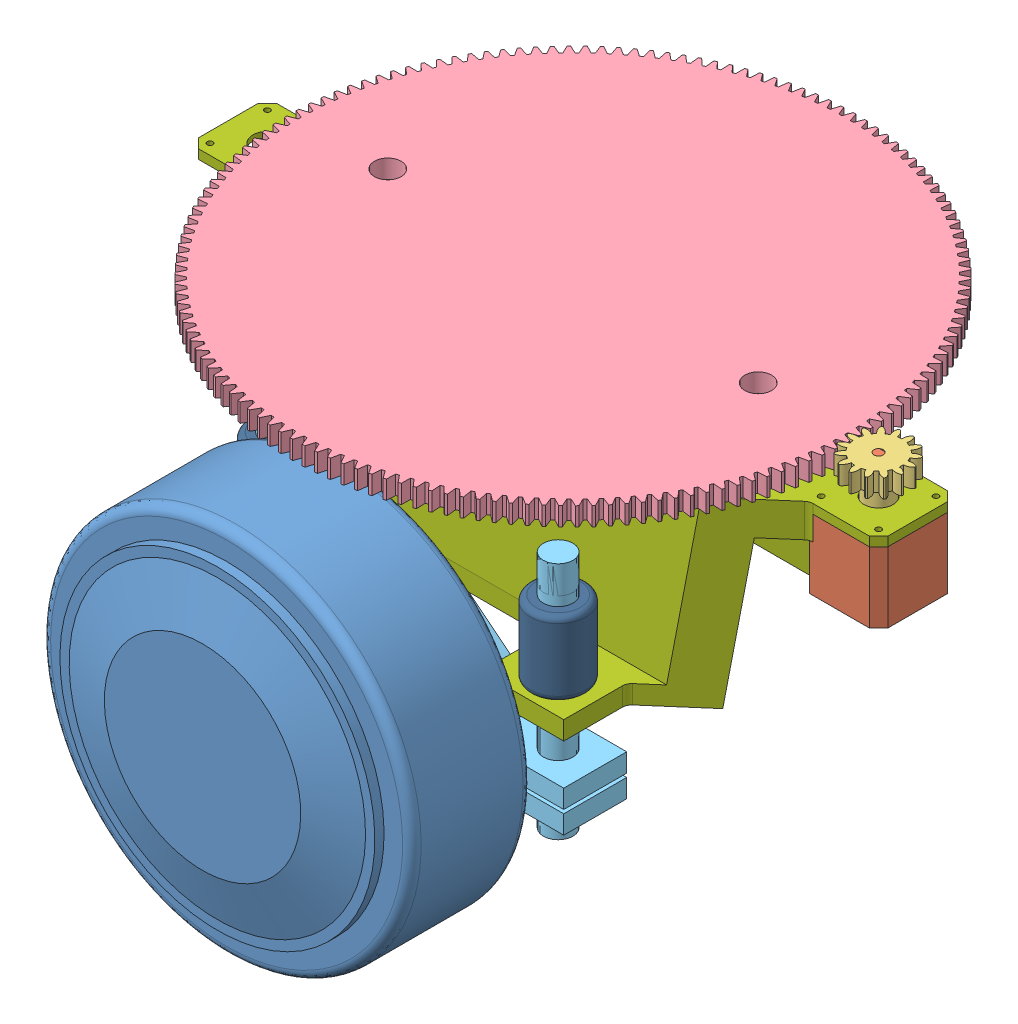
SolidWorks assembly Привод поворотный, configuration 00. Lengths in mm.
Overall size (374.92 225 352).
16 component instances, 12 part files, 37 mates.
Components (placement in the parent):
- Мотор-колесо ZLLG80ASM800-1: Мотор-колесо ZLLG80ASM800 [1 крепление] at (0 0 154.5) x (0 0 1) z (0 1 0) size (133 200 200)
- Мотор-колесо ZLLG80ASM800-2: Мотор-колесо ZLLG80ASM800 [1 крепление] at (0 0 -154.5) x (0 0 -1) z (0 -1 0) size (133 200 200) (hidden)
- 17HS4401 (Nema17)-1: 17HS4401 (Nema17) [--] at (165 99.5 0) x (1 0 0) z (0 1 0) size (42.3 42.3 63.5)
- Шестерня малая-3: Шестерня малая [DIN - Spur gear 2M 15T 20PA 10FW ---S15B15H23L5N] at (165 115 0) x (0 1 0) z (-0.600266 0 0.799801) size (23 33.72 33.9)
- Шестерня большая-7: Шестерня большая [Z150] at (0 125 0) x (0 -1 0) z (0 0 1) size (87 303.96 304)
- Кулак привода 2-1: Кулак привода 2 [--] at (0 0 101) size (192 129 34)
- Пружина 22х22х2-1: Пружина 22х22х2 [--] at (-76 -15.75 84) size (24 22 24.59)
- Каретка-1: Каретка [--] at (0 99.5 0) size (372.3 98.5 202)
- Ступица 2007910А-1: Ступица 2007910А [00] at (0 97 0) x (0 -1 0) z (0 0 1) size (50 94.04 94.04)
  - Подшипник 2007910А (72х50х15)-1: Подшипник 2007910А (72х50х15) [--] at origin size (15 72 72)
  - Подшипник 2007910А (72х50х15)-2: Подшипник 2007910А (72х50х15) [--] at (-5 0 0) x (-1 0 0) z (0 -0.924225 -0.381849) size (15 72 72)
  - Обойма 2007910А (2шт)-1: Обойма 2007910А (2шт) [--] at origin size (47 82 82)
- Линейный подшипник (16х30х40)-1: Линейный подшипник (16х30х40) [--] at (-76 36 84) x (1 0 0) z (0 -1 0) size (30 30 40)
- Линейный подшипник (16х30х40)-2: Линейный подшипник (16х30х40) [--] at (76 36 84) x (-1 0 0) z (0 1 0) size (30 30 40)
- Гайка (ГОСТ ISO 4032-2014)-1: Гайка (ГОСТ ISO 4032-2014) [Гайка М42 (ГОСТ ISO 4032)] at (0 60 0) x (1 0 0) z (0 1 0) size (65 71.3 34)
- Кольцо ступицы-1: Кольцо ступицы [--] at (0 82 0) size (61.75 5 61.75)
Mates (geometry in assembly coordinates):
- Расстояние1: distance = 200 mm: plane of Мотор-колесо ZLLG80ASM800-1 through (53 0 200) normal (0 0 1); plane of assembly through (0 0 0) normal (0 0 1)
- Параллельность2: parallel: plane of Мотор-колесо ZLLG80ASM800-1 through (-291587.9 -6 67) normal (0 -1 0); plane of assembly through (0 0 0) normal (0 1 0)
- Совпадение3: coincident: plane of Мотор-колесо ZLLG80ASM800-1 through (0 0 154.5) normal (0 1 0); plane of assembly through (0 0 0) normal (0 1 0)
- Совпадение4: coincident: plane of Мотор-колесо ZLLG80ASM800-1 through (0 0 154.5) normal (1 0 0); plane of assembly through (0 0 0) normal (1 0 0)
- Совпадение5: coincident: plane of ? through (0 115 0) normal (0 1 0); plane of assembly through (0 115 0) normal (0 1 0)
- Совпадение6: coincident: plane of ? through (0 115 0) normal (0 0 1); plane of assembly through (0 0 0) normal (0 0 1)
- Совпадение7: coincident: plane of ? through (0 115 0) normal (1 0 0); plane of assembly through (0 0 0) normal (1 0 0)
- Совпадение15: coincident: plane of 17HS4401 (Nema17)-1 through (165 99.5 0) normal (0 0 -1); plane of assembly through (0 0 0) normal (0 0 1)
- Расстояние3: distance = 165 mm: plane of 17HS4401 (Nema17)-1 through (165 99.5 0) normal (1 0 0); plane of assembly through (0 0 0) normal (1 0 0)
- Концентричный1: concentric: cylinder of 17HS4401 (Nema17)-1 through (165 125 0) axis (0 -1 0) radius 2.5; cylinder of Шестерня малая-3 through (165 138.0001 0) axis (0 -1 0) radius 2.5
- Совпадение16: coincident: plane of 17HS4401 (Nema17)-1 through (165 125 0) normal (0 1 0); plane of Шестерня малая-3 through (165 125 0) normal (0 1 0)
- Совпадение17: coincident: plane of Шестерня большая-7 through (0 115 0) normal (0 -1 0); plane of assembly
- Совпадение18: coincident: plane of Шестерня большая-7 through (0 125 0) normal (1 0 0); plane of assembly through (0 0 0) normal (1 0 0)
- Совпадение19: coincident: plane of Шестерня большая-7 through (0 125 0) normal (0 0 1); plane of assembly through (0 0 0) normal (0 0 1)
- Совпадение20: coincident: plane of Шестерня малая-3 through (165 125 0) normal (0 1 0); plane of Шестерня большая-7 through (0 125 0) normal (0 1 0)
- Совпадение21: coincident: plane of Мотор-колесо ZLLG80ASM800-1 through (0 0 101) normal (0 0 -1); plane of Кулак привода 2-1 through (0 0 101) normal (0 0 1)
- Совпадение22: coincident: plane of Кулак привода 2-1 through (0 0 101) normal (1 0 0); plane of assembly through (0 0 0) normal (1 0 0)
- Совпадение23: coincident: plane of Кулак привода 2-1 through (0 0 101) normal (0 1 0); plane of assembly through (0 0 0) normal (0 1 0)
- Совпадение24: coincident: plane of Кулак привода 2-1 through (-51 -16 -37.7855) normal (0 1 0); plane of Пружина 22х22х2-1 through (-93.7909 -16 72.0003) normal (0 -1 0)
- Расстояние5: distance = 20 mm: plane of Пружина 22х22х2-1 through (-76 -15.75 84) normal (1 0 0); plane of Кулак привода 2-1 through (-96 -16 -37.7855) normal (-1 0 0)
- Симметричный1: symmetric: plane of Кулак привода 2-1 through (8 0 67) normal (0 0 -1); plane of Кулак привода 2-1 through (0 0 101) normal (0 0 1); plane of Пружина 22х22х2-1 through (-76 -15.75 84) normal (0 0 1)
- Совпадение25: coincident: plane of 17HS4401 (Nema17)-1 through (165 99.5 0) normal (0 1 0); plane of Каретка-1 through (0 99.5 0) normal (0 1 0)
- Совпадение26: coincident: plane of Каретка-1 through (0 99.5 0) normal (0 0 1); plane of assembly through (0 0 0) normal (0 0 1)
- Совпадение27: coincident: plane of Каретка-1 through (0 99.5 0) normal (1 0 0); plane of assembly through (0 0 0) normal (1 0 0)
- Расстояние6: distance = 2 mm: plane of Шестерня большая-7 through (0 115 0) normal (0 -1 0); plane of Ступица 2007910А-1/Подшипник 2007910А (72х50х15)-2 through (13.1971 117 -31.9421) normal (0 1 0)
- Совпадение29: coincident: plane of Шестерня большая-7 through (0 125 0) normal (0 0 1); plane of ? through (0 97 0) normal (0 0 1)
- Совпадение30: coincident: plane of Шестерня большая-7 through (0 125 0) normal (1 0 0); plane of ? through (0 97 0) normal (1 0 0)
- Совпадение31: coincident: plane of Каретка-1 through (186.15 16 101) normal (0 1 0); plane of Линейный подшипник (16х30х40)-1 through (-76 16 84) normal (0 -1 0)
- Концентричный2: concentric: circle of Пружина 22х22х2-1; cylinder of Линейный подшипник (16х30х40)-1 through (-76 16 84) axis (0 1 0) radius 15
- Расстояние7: distance = 5 mm: plane of Гайка (ГОСТ ISO 4032-2014)-1 through (0 77 -30) normal (0 1 0); plane of Ступица 2007910А-1/Подшипник 2007910А (72х50х15)-1 through (34.561 82 0) normal (0 -1 0)
- Концентричный3: concentric: circle of Ступица 2007910А-1/Подшипник 2007910А (72х50х15)-1; cylinder of Гайка (ГОСТ ISO 4032-2014)-1 through (0 212.7402 0) axis (0 1 0) radius 17.1029
- Перпендикулярность1: perpendicular: line of Каретка-1 through (132.8855 86.5 -35) axis (-1 0 0); plane of Гайка (ГОСТ ISO 4032-2014)-1 through (32.5 43 18.7639) normal (1 0 0)
- Совпадение34: coincident: plane of Ступица 2007910А-1/Подшипник 2007910А (72х50х15)-1 through (34.561 82 0) normal (0 -1 0); plane of Кольцо ступицы-1 through (0 82 0) normal (0 1 0)
- Совпадение35: coincident: plane of Кольцо ступицы-1 through (0 82 0) normal (0 0 1); plane of assembly through (0 0 0) normal (0 0 1)
- Совпадение37: coincident: plane of Кольцо ступицы-1 through (0 82 0) normal (1 0 0); plane of assembly through (0 0 0) normal (1 0 0)
- Совпадение38: coincident: plane of Шестерня малая-3 through (165 125 0) normal (0 1 0); plane of Шестерня большая-7 through (0 125 0) normal (0 1 0)
- Концентричный4: concentric: cylinder of 17HS4401 (Nema17)-1 through (165 125 0) axis (0 -1 0) radius 2.5; circle of ?; cylinder of Шестерня малая-3 through (165 138.0001 0) axis (0 -1 0) radius 2.5; circle of ?
